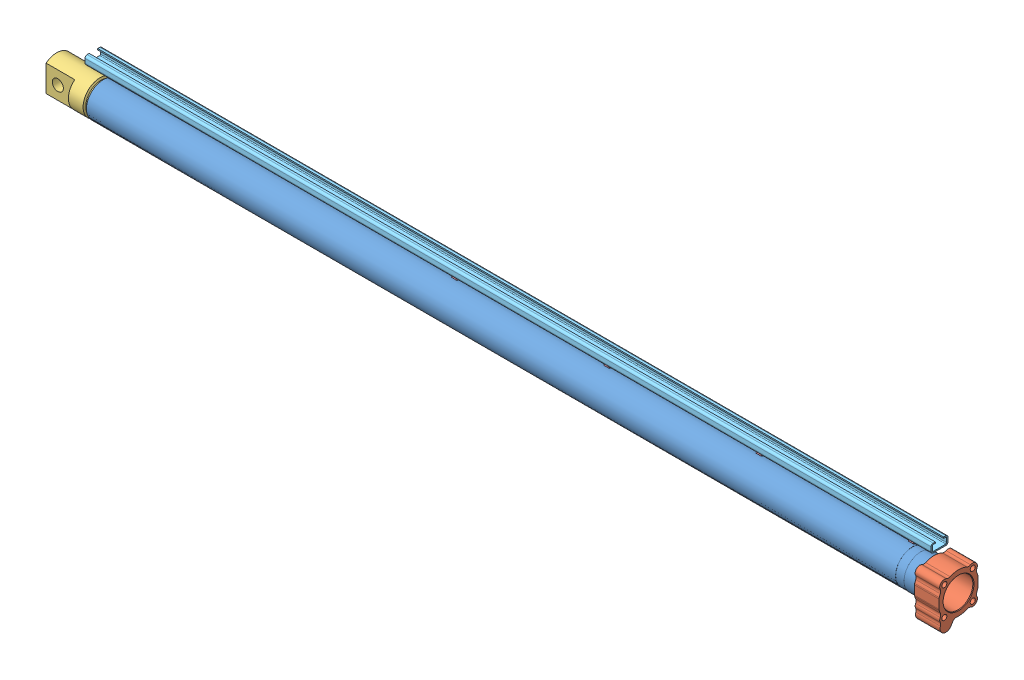
SolidWorks assembly 6344545, configuration Default. Lengths in mm.
Overall size (2132.04 127.53 92).
8 component instances, 5 part files, 15 mates.
Components (placement in the parent):
- 6344546-1: 6344546 [Default] at (-2024 0 0) x (-1 0 0) z (0 0 -1) size (1968 80 80)
- 6344547-1: 6344547 [Default] at (1 0 0) x (0 0 -1) z (-1 0 0) size (92 113.03 58)
- 6344548-1: 6344548 [Default] at (-2104 0 0) x (-1 0 0) z (0 0 1) size (112.04 80 80)
- 6344549-1: 6344549 [Default] at (-119 0 0) x (0 0 1) z (-1 0 0) size (35.49 20.05 12)
- 6302411-1: 6302411 [2000] at (-70 42 -25) x (0 0 1) z (-1 0 0) size (40 20 2000)
- 6344549-2: 6344549 [Default] at (-479 0 0) x (0 0 1) z (-1 0 0) size (35.49 20.05 12)
- 6344549-3: 6344549 [Default] at (-839 0 0) x (0 0 1) z (-1 0 0) size (35.49 20.05 12)
- 6344549-4: 6344549 [Default] at (-1199 0 0) x (0 0 1) z (-1 0 0) size (35.49 20.05 12)
Mates (geometry in assembly coordinates):
- Coincident11: coincident aligned: plane of 6344547-1 through (0 -90 0) normal (1 0 0); plane of assembly through (0 0 0) normal (1 0 0)
- Concentric4: concentric aligned: cylinder of 6344546-1 through (-1901.2158 0 0) axis (1 0 0) radius 40; cylinder of 6344547-1 through (-59 0 0) axis (1 0 0) radius 47.5
- Concentric5: concentric: cylinder of 6344547-1 through (-59 0 0) axis (1 0 0) radius 47.5
- Coincident12: coincident anti-aligned: plane of 6344546-1 through (-56 37.5 0) normal (1 0 0); plane of 6344547-1 through (-56 -37.5 0) normal (-1 0 0)
- Parallel6: parallel anti-aligned: plane of 6344547-1 through (1 0 0) normal (0 0 -1); plane of assembly through (0 0 0) normal (0 0 1)
- Parallel7: parallel anti-aligned: plane of 6344546-1 through (-2024 0 0) normal (0 0 -1); plane of assembly through (0 0 0) normal (0 0 1)
- Distance4: distance = 12 mm anti-aligned: plane of 6344547-1 through (-58 -37.5 0) normal (-1 0 0); plane of 6302411-1 through (-70 57 -10) normal (1 0 0)
- Distance5: distance = 42 mm anti-aligned: plane of 6302411-1 through (-2070 42 -10) normal (0 -1 0); plane of assembly through (0 0 0) normal (0 1 0)
- Distance6: distance = 25 mm aligned: plane of 6302411-1 through (-70 42 -25) normal (0 0 1); plane of assembly through (0 0 0) normal (0 0 1)
- Parallel8: parallel anti-aligned: plane of 6302411-1 through (-2070 42 -10) normal (0 -1 0); plane of 6344549-1 through (-125 42 -39.0903) normal (0 1 0)
- Concentric9: concentric aligned: cylinder of 6344546-1 through (-1901.2158 0 0) axis (1 0 0) radius 40; cylinder of 6344549-1 through (-125 0 0) axis (1 0 0) radius 40.25
- Distance7: distance = 55 mm anti-aligned: plane of 6344547-1 through (-58 -37.5 0) normal (-1 0 0); plane of 6344549-1 through (-113 40.75 -7.8541) normal (1 0 0)
- Coincident20: coincident anti-aligned: plane of 6344546-1 through (-2024 35 0) normal (-1 0 0); plane of 6344548-1 through (-2024 -36 0) normal (1 0 0)
- Concentric10: concentric aligned: cylinder of 6344546-1 through (-1901.2158 0 0) axis (1 0 0) radius 35; cylinder of 6344548-1 through (-2013.4265 0 0) axis (1 0 0) radius 35
- Parallel9: parallel aligned: plane of 6344548-1 through (-2104 0 0) normal (0 0 1); plane of assembly through (0 0 0) normal (0 0 1)
